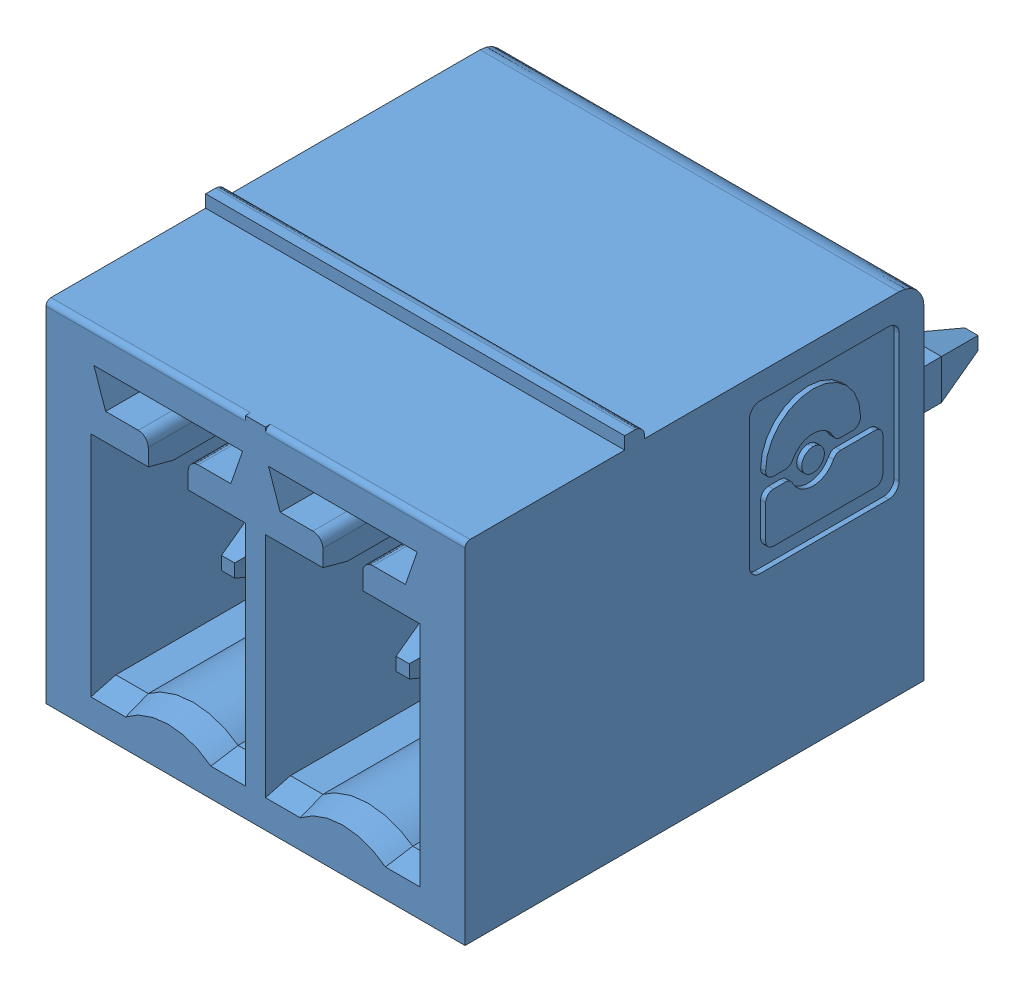
SolidWorks assembly pxc_1843606_03_MCV-1-5-2-G-3-5_3D, configuration Default. Lengths in mm.
Overall size (8.4 7.25 12.6).
2 component instances, 1 part files, 0 mates.
Components (placement in the parent):
- pxc_1843606_03_MCV-1-5-2-G-3-5_3D.stp-1: pxc_1843606_03_MCV-1-5-2-G-3-5_3D.stp [Default] at origin size (8.4 7.25 12.6)
  - MCV1_5-2-G_3_5.stp-1: MCV1_5-2-G_3_5.stp [Default] at (2.45 0 0) x (0 0 1) z (-1 0 0) size (12.6 7.25 8.4)
